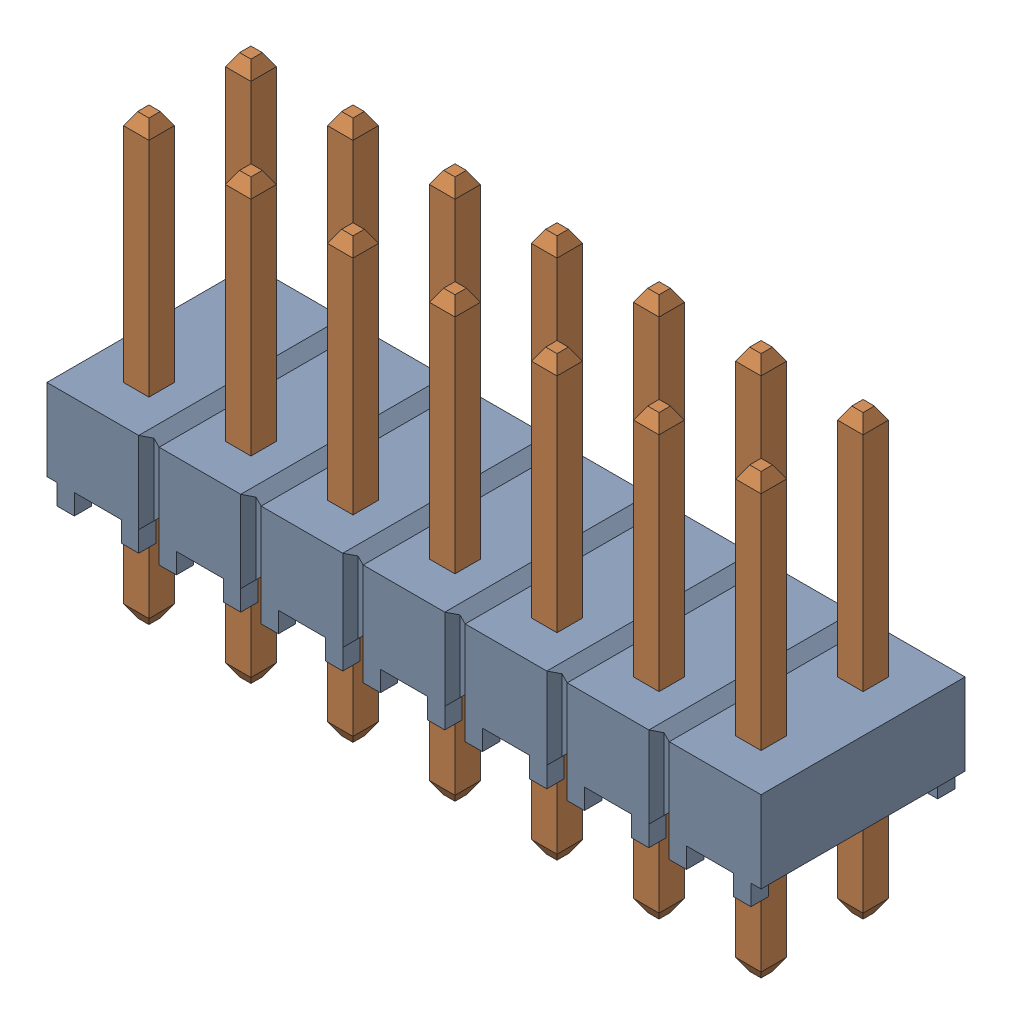
SolidWorks assembly TSW_107_07_L_D, configuration Default. Lengths in mm.
Overall size (17.78 10.92 5.08).
2 component instances, 2 part files, 0 mates.
Components (placement in the parent):
- _TSW_107_07_L_D_body_2-1: _TSW_107_07_L_D_body_2 [Default] at origin size (17.78 2.54 5.08)
- _T_1S6_07_TSW_1_07_7_D_4-1: _T_1S6_07_TSW_1_07_7_D_4 [Default] at (0 -2.54 0) size (16.13 10.92 3.43)
